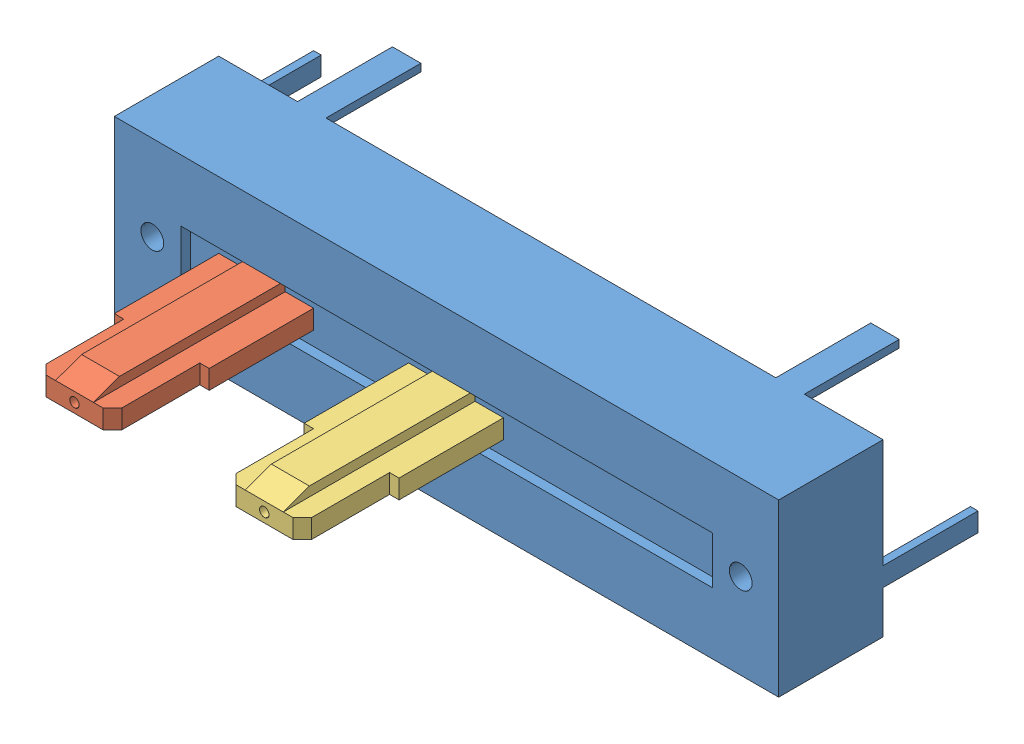
SolidWorks assembly fader, configuration Standard. Lengths in mm.
Overall size (35 9 20.1).
3 component instances, 3 part files, 5 mates.
Components (placement in the parent):
- glider35_20mm_range-1: glider35_20mm_range [Standard] at (-50.137 36.8246 -5.25) size (35 9 10.5)
- glider-1: glider [Standard] at (-60.137 36.8246 2.5) x (1 0 0) z (0 -1 0) size (5 10.1 2)
- glider-center-1: glider-center [Standard] at (-50.137 36.8246 2.5) x (1 0 0) z (0 -1 0) size (5 10.1 2)
Mates (geometry in assembly coordinates):
- Deckungsgleich1: coincident anti-aligned: plane of glider35_20mm_range-1 through (-50.137 36.8246 -0.25) normal (0 0 1); plane of glider-1 through (-62.637 36.3246 -0.25) normal (0 0 -1)
- Abstand1: distance = 0.25 mm anti-aligned: plane of glider-1 through (-60.137 37.8246 2.5) normal (0 1 0); plane of glider35_20mm_range-1 through (-64.137 38.0746 -0.25) normal (0 -1 0)
- LimitAbstand4: limit distance = 21.5 mm anti-aligned: plane of glider-1 through (-57.637 36.3246 5.25) normal (1 0 0); plane of glider35_20mm_range-1 through (-36.137 38.0746 -0.25) normal (-1 0 0)
- Deckungsgleich2: coincident anti-aligned: plane of glider35_20mm_range-1 through (-50.137 36.8246 -0.25) normal (0 0 1); plane of glider-center-1 through (-52.637 36.3246 -0.25) normal (0 0 -1)
- Konzentrisch2: concentric aligned: cylinder of glider35_20mm_range-1 through (-50.137 36.8246 -10.25) axis (0 0 1) radius 0.25; cylinder of glider-center-1 through (-50.137 36.8246 -0.25) axis (0 0 1) radius 0.25
